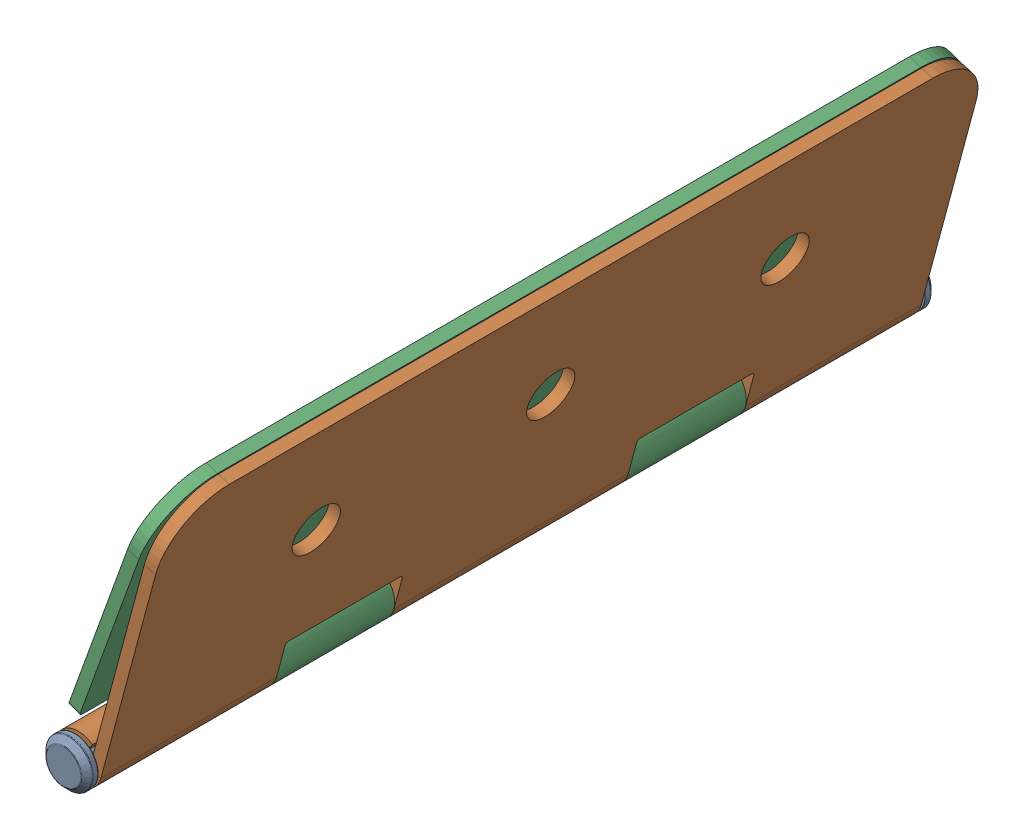
SolidWorks assembly Hinge Assembly, configuration Default. Lengths in mm.
Overall size (61.29 126.46 362.5).
3 component instances, 3 part files, 4 mates.
Components (placement in the parent):
- Pin for Door-1: Pin for Door [Default] at origin size (20 20 362.5)
- Door Hinge-1: Door Hinge [Default] at (21.0446 56.9169 35.0125) x (0 0 -1) z (-0.96574 0.259512 0) size (350 125 20)
- Door Hinge Part 2-1: Door Hinge Part 2 [Default] at (17.1225 65.9405 -34.9875) x (0 0 1) z (0.940497 -0.339802 0) size (350 125 20)
Mates (geometry in assembly coordinates):
- Concentric2: concentric anti-aligned: cylinder of Pin for Door-1 through (0 0 176.2625) axis (0 0 -1) radius 4.625; cylinder of Door Hinge-1 through (0 0 50.0125) axis (0 0 1) radius 5
- Width1: width aligned: plane of Pin for Door-1 through (0 0 176.2625) normal (0 0 -1); plane of Door Hinge-1 through (0 0 -176.2375) normal (0 0 1); plane of Pin for Door-1 through (7.0623 -12.2525 -174.9875) normal (0 0 -1); plane of Door Hinge-1 through (39.5013 108.4649 175.0125) normal (0 0 1)
- Hinge1: hinge anti-aligned: cylinder of Door Hinge Part 2-1 through (0 0 50.0125) axis (0 0 -1) radius 5; cylinder of Door Hinge Part 2-1 through (0 0 50.0125) axis (0 0 1) radius 5; plane of Door Hinge-1 through (0 0 -99.9875) normal (0 0 -1); plane of Door Hinge-1 through (0 0 -99.9875) normal (0 0 1)
- LimitAngle2: limit planar angle = 0.084189 rad anti-aligned: plane of Door Hinge Part 2-1 through (34.3747 109.8562 -174.9875) normal (0.940497 -0.339802 0); plane of Door Hinge-1 through (34.6726 109.7625 175.0125) normal (-0.96574 0.259512 0)
